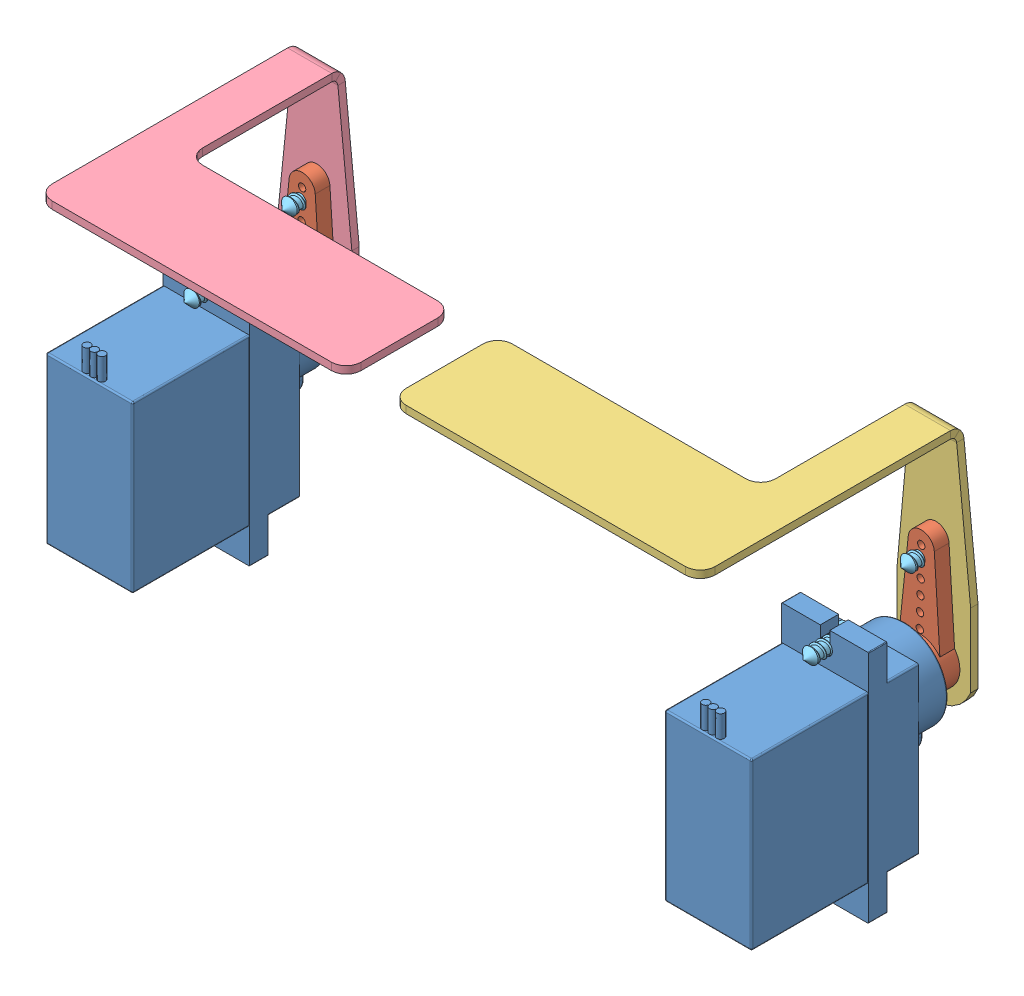
SolidWorks assembly PU, configuration Predeterminado. Lengths in mm.
Overall size (95.94 49.57 37.38).
14 component instances, 6 part files, 25 mates.
Components (placement in the parent):
- sg90-1: sg90 [Default] at (201.5956 -166.7354 155.7219) x (0 -1 0) z (1 0 0) size (31.9 29.9 11.8)
- sg90-2: sg90 [Default] at (117.452 -166.7354 155.7219) x (0 -1 0) z (1 0 0) size (31.9 29.9 11.8)
- SG90 plastic Horn-1: SG90 plastic Horn [Default] at (123.352 -172.6354 127.0219) x (0.017141 0.999853 0) z (-0.999853 0.017141 0) size (19.4 4 7.07)
- SG90 plastic Horn-2: SG90 plastic Horn [Default] at (207.4956 -172.6354 127.0219) x (0.020276 0.999794 0) z (-0.999794 0.020276 0) size (19.4 4 7.07)
- Pusher_left-1: Pusher_left [Predeterminado] at (252.6438 -158.8738 124.0219) x (-1 0 0) z (0 0 -1) size (44 33.65 35.77)
- Pusher_right-1: Pusher_right [Predeterminado] at (78.2037 -158.8738 125.0219) size (44 33.65 35.77)
- M2x6 SelfTap Screw-1: M2x6 SelfTap Screw [Predeterminado] at (207.4956 -164.3354 136.8219) x (-0.923728 -0.383049 0) z (0 0 -1) size (3.4 3.28 6)
- M2x6 SelfTap Screw-2: M2x6 SelfTap Screw [Predeterminado] at (207.4956 -191.6354 136.3219) x (-0.923728 -0.383049 0) z (0 0 -1) size (3.4 3.28 6)
- M2x6 SelfTap Screw-3: M2x6 SelfTap Screw [Predeterminado] at (123.352 -164.3354 136.8219) x (-0.993348 0.115149 0) z (0 0 -1) size (3.4 3.28 6)
- M2x6 SelfTap Screw-4: M2x6 SelfTap Screw [Predeterminado] at (123.352 -191.6354 136.8219) x (-0.923728 -0.383049 0) z (0 0 -1) size (3.4 3.28 6)
- (M2_3_mm)_90116A007_METRIC 316 SS PAN HEAD PHILLIPS MACHINE SCREW-1: (M2_3_mm)_90116A007_METRIC 316 SS PAN HEAD PHILLIPS MACHINE SCREW [90116A007] at (123.352 -172.6354 127.0219) x (-0.923728 -0.383049 0) z (0 0 -1) size (4 4 4.68)
- (M2_3_mm)_90116A007_METRIC 316 SS PAN HEAD PHILLIPS MACHINE SCREW-2: (M2_3_mm)_90116A007_METRIC 316 SS PAN HEAD PHILLIPS MACHINE SCREW [90116A007] at (207.4956 -172.6354 127.0219) x (-0.923728 -0.383049 0) z (0 0 -1) size (4 4 4.68)
- M2x6 SelfTap Screw-5: M2x6 SelfTap Screw [Predeterminado] at (123.352 -160.1354 123.5219) x (-0.923728 -0.383049 0) z (0 0 -1) size (3.4 3.28 6)
- M2x6 SelfTap Screw-6: M2x6 SelfTap Screw [Predeterminado] at (207.4956 -160.1354 123.5219) x (-0.923728 -0.383049 0) z (0 0 -1) size (3.4 3.28 6)
Mates (geometry in assembly coordinates):
- Coincidente326: coincident: plane of sg90-1 through (207.4956 -172.6354 129.0219) normal (0 0 -1); plane of SG90 plastic Horn-2 through (207.5438 -170.2609 129.0219) normal (0 0 1)
- Concéntrica163: concentric: circle of sg90-1; circle of SG90 plastic Horn-2
- Distancia47: distance = 0.5 mm: plane of M2x6 SelfTap Screw-1 through (207.4956 -164.3354 136.8219) normal (0 0 -1); plane of sg90-1 through (201.5956 -162.0354 137.3219) normal (0 0 -1)
- Concéntrica166: concentric: circle of sg90-1; circle of M2x6 SelfTap Screw-1
- Distancia48: distance = 1 mm: plane of M2x6 SelfTap Screw-2 through (207.4956 -191.6354 136.3219) normal (0 0 -1); plane of sg90-1 through (213.3956 -193.9354 137.3219) normal (0 0 -1)
- Concéntrica167: concentric: circle of sg90-1; circle of M2x6 SelfTap Screw-2
- Coincidente325: coincident: plane of sg90-2 through (123.352 -172.6354 129.0219) normal (0 0 -1); plane of SG90 plastic Horn-1 through (123.3927 -170.2608 129.0219) normal (0 0 1)
- Concéntrica162: concentric: circle of sg90-2; circle of SG90 plastic Horn-1
- Distancia49: distance = 0.5 mm: plane of M2x6 SelfTap Screw-3 through (123.352 -164.3354 136.8219) normal (0 0 -1); plane of sg90-2 through (117.452 -162.0354 137.3219) normal (0 0 -1)
- Concéntrica168: concentric: circle of sg90-2; circle of M2x6 SelfTap Screw-3
- Distancia50: distance = 0.5 mm: plane of M2x6 SelfTap Screw-4 through (123.352 -191.6354 136.8219) normal (0 0 -1); plane of sg90-2 through (129.252 -193.9354 137.3219) normal (0 0 -1)
- Concéntrica169: concentric: circle of sg90-2; circle of M2x6 SelfTap Screw-4
- Coincidente329: coincident: plane of SG90 plastic Horn-1 through (123.4125 -169.1009 125.0219) normal (0 0 -1); plane of Pusher_right-1 through (128.3547 -126.5811 125.0219) normal (0 0 1)
- Concéntrica165: concentric: circle of SG90 plastic Horn-1; circle of Pusher_right-1
- Coincidente327: coincident: plane of SG90 plastic Horn-2 through (207.5673 -169.1011 125.0219) normal (0 0 -1); plane of Pusher_left-1 through (202.2679 -126.5811 125.0219) normal (0 0 1)
- Concéntrica164: concentric: circle of SG90 plastic Horn-2; circle of Pusher_left-1
- Paralelo59: parallel: plane of Pusher_left-1 through (202.2679 -144.37 143.3416) normal (0 1 0); plane of Pusher_right-1 through (128.3547 -144.37 143.3415) normal (0 1 0)
- Coincidente335: coincident: plane of Pusher_left-1 through (202.2679 -126.5811 124.0219) normal (0 0 -1); plane of (M2_3_mm)_90116A007_METRIC 316 SS PAN HEAD PHILLIPS MACHINE SCREW-2 through (207.4956 -172.6354 124.0219) normal (0 0 1)
- Concéntrica170: concentric: circle of Pusher_left-1; circle of (M2_3_mm)_90116A007_METRIC 316 SS PAN HEAD PHILLIPS MACHINE SCREW-2
- Distancia51: distance = 0.5 mm: plane of Pusher_left-1 through (202.2679 -126.5811 124.0219) normal (0 0 -1); plane of M2x6 SelfTap Screw-6 through (207.4956 -160.1354 123.5219) normal (0 0 -1)
- Concéntrica172: concentric: circle of Pusher_left-1; circle of M2x6 SelfTap Screw-6
- Coincidente336: coincident: plane of Pusher_right-1 through (128.3547 -126.5811 124.0219) normal (0 0 -1); plane of (M2_3_mm)_90116A007_METRIC 316 SS PAN HEAD PHILLIPS MACHINE SCREW-1 through (123.352 -172.6354 124.0219) normal (0 0 1)
- Concéntrica171: concentric: circle of Pusher_right-1; circle of (M2_3_mm)_90116A007_METRIC 316 SS PAN HEAD PHILLIPS MACHINE SCREW-1
- Distancia52: distance = 0.5 mm: plane of M2x6 SelfTap Screw-5 through (123.352 -160.1354 123.5219) normal (0 0 -1); plane of Pusher_right-1 through (128.3547 -126.5811 124.0219) normal (0 0 -1)
- Concéntrica173: concentric: circle of Pusher_right-1; circle of M2x6 SelfTap Screw-5
